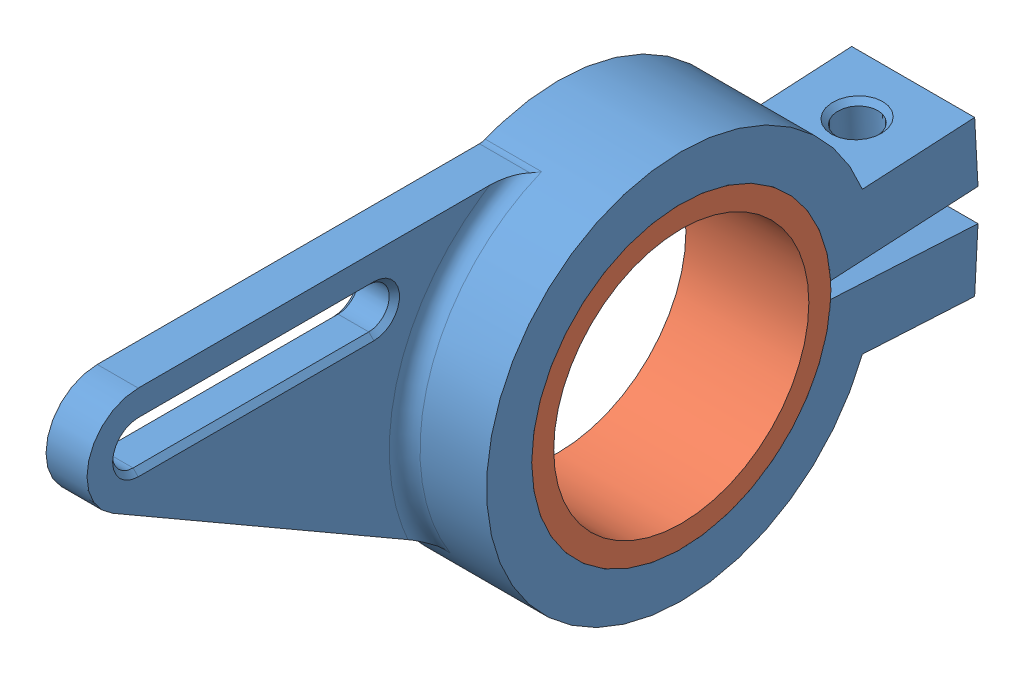
SolidWorks assembly MotorMount A, configuration Défaut. Lengths in mm.
Overall size (12 38.38 78.96).
3 component instances, 2 part files, 2 mates.
Components (placement in the parent):
- MotorMount .step-1: MotorMount .step [Défaut] at origin size (12 38.38 78.96)
  - MotorMount_1.step-1: MotorMount_1.step [Défaut] at origin size (12 38.38 78.96)
- Ajout MotorMount-2: Ajout MotorMount [Défaut] at (27 0 0) x (0 0 1) z (-1 0 0) size (29.2 29.2 12)
Mates (geometry in assembly coordinates):
- Coaxiale7: concentric: cylinder of MotorMount .step-1/MotorMount_1.step-1 through (27 25 -33.5) axis (-1 0 0) radius 14.6; cylinder of Ajout MotorMount-2 through (15 25 -33.5) axis (1 0 0) radius 14.6
- Coïncidente2: coincident: circle of MotorMount .step-1/MotorMount_1.step-1; circle of Ajout MotorMount-2
